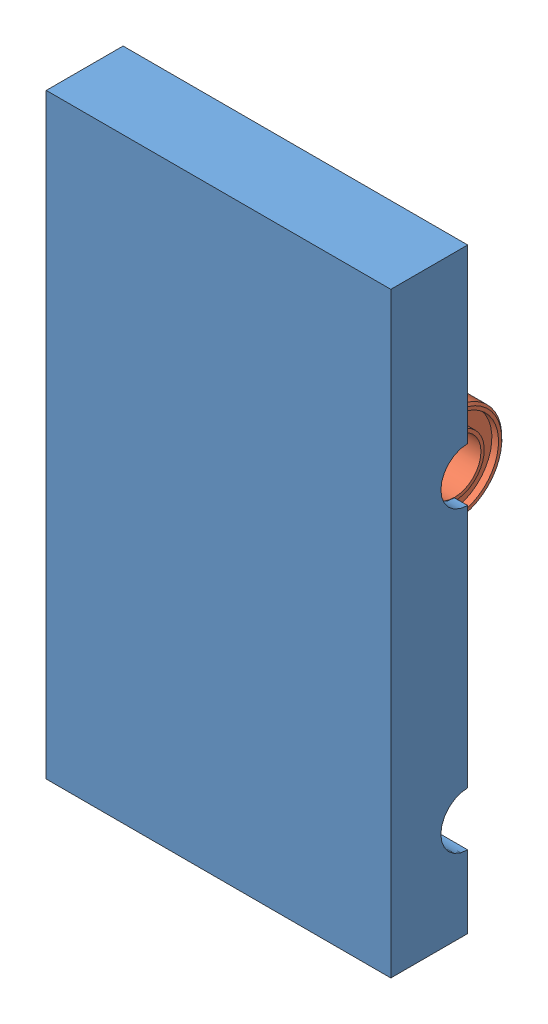
SolidWorks assembly SE-X-Carriage, configuration Predeterminado. Lengths in mm.
Overall size (52 90 22.04).
4 component instances, 2 part files, 6 mates.
Components (placement in the parent):
- X-Carriage-1: X-Carriage [Predeterminado] at (-23.0327 -49.5858 84.2) size (52 90 15.6)
- LM8UU-1: LM8UU [Default] at (-9.0327 10.4142 84.2) x (1 0 0) z (0 -0.510186 0.860064) size (24 15 15)
- LM8UU-2: LM8UU [Default] at (14.9673 10.4142 84.2) x (1 0 0) z (0 -0.570337 0.821411) size (24 15 15)
- LM8UU-3: LM8UU [Default] at (2.9673 -34.5858 84.2) size (24 15 15)
Mates (geometry in assembly coordinates):
- Concéntrica1: concentric anti-aligned: cylinder of X-Carriage-1 through (-21.0327 10.4142 84.2) axis (1 0 0) radius 7.55; cylinder of LM8UU-1 through (-54.7222 10.4142 84.2) axis (-1 0 0) radius 7.5
- Concéntrica2: concentric anti-aligned: cylinder of X-Carriage-1 through (-21.0327 10.4142 84.2) axis (1 0 0) radius 7.55; cylinder of LM8UU-2 through (-30.7222 10.4142 84.2) axis (-1 0 0) radius 7.5
- Concéntrica3: concentric anti-aligned: cylinder of X-Carriage-1 through (-9.0327 -34.5858 84.2) axis (1 0 0) radius 7.55; cylinder of LM8UU-3 through (-42.7222 -34.5858 84.2) axis (-1 0 0) radius 7.5
- Coincidente1: coincident anti-aligned: plane of X-Carriage-1 through (-9.0327 -34.5858 84.2) normal (1 0 0); plane of LM8UU-3 through (-9.0327 -34.5858 84.2) normal (-1 0 0)
- Coincidente2: coincident anti-aligned: plane of X-Carriage-1 through (-21.0327 10.4142 84.2) normal (1 0 0); plane of LM8UU-1 through (-21.0327 10.4142 84.2) normal (-1 0 0)
- Coincidente3: coincident anti-aligned: plane of X-Carriage-1 through (26.9673 10.4142 84.2) normal (-1 0 0); plane of LM8UU-2 through (26.9673 10.4142 84.2) normal (1 0 0)
